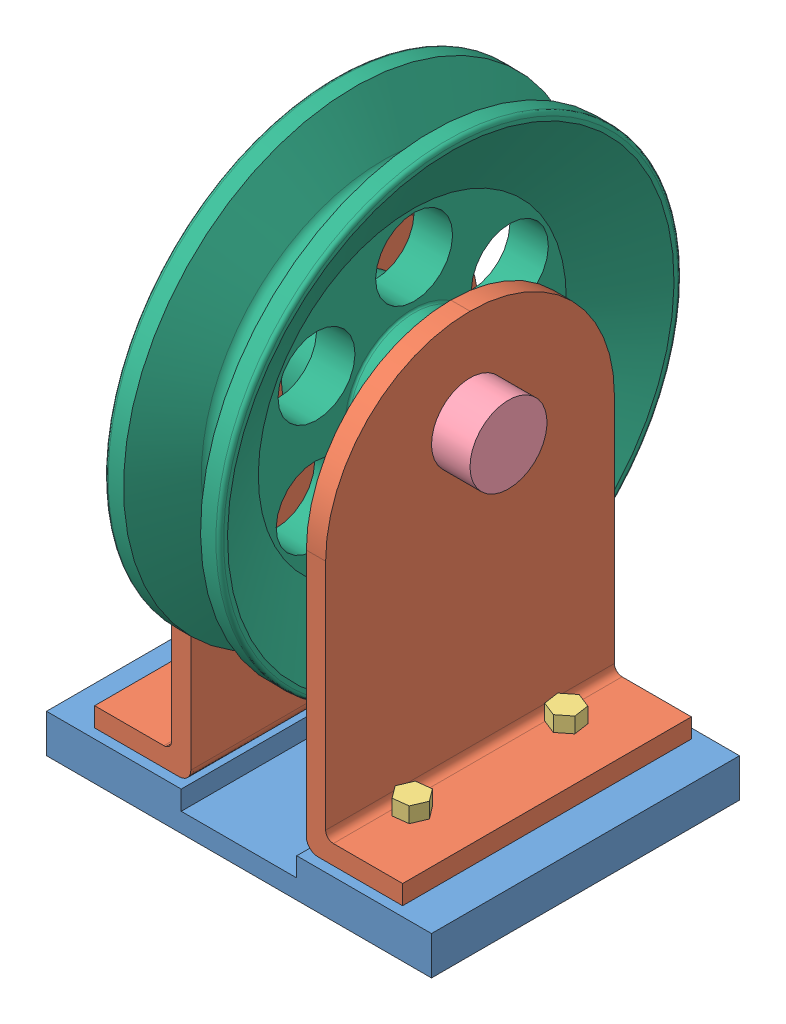
SolidWorks assembly pulley-assembly, configuration Default. Lengths in mm.
Overall size (2540 3846.4 3097.4).
10 component instances, 6 part files, 24 mates.
Components (placement in the parent):
- Base Plate-1: Base Plate [Default] at (1082.0609 1041.9855 1985.3264) size (2540 254 2032)
- Bracket-2: Bracket [Default] at (1463.0609 1295.9855 1032.8264) x (0 0 -1) z (1 0 0) size (1905 2724.15 698.5)
- Bracket-3: Bracket [Default] at (701.0609 1295.9855 2937.8264) x (0 0 1) z (-1 0 0) size (1905 2724.15 698.5)
- Bolt-1: Bolt [Default] at (1717.0609 1422.9855 2493.3264) x (0.390029 0 -0.920802) z (0.920802 0 0.390029) size (202.45 355.6 175.33)
- Bolt-2: Bolt [Default] at (1717.0609 1422.9855 1477.3264) x (0.783764 0 -0.621058) z (0.621058 0 0.783764) size (202.45 355.6 175.33)
- Bolt-3: Bolt [Default] at (447.0609 1422.9855 2493.3264) x (0.04355 0 0.999051) z (-0.999051 0 0.04355) size (202.45 355.6 175.33)
- Bolt-4: Bolt [Default] at (447.0609 1422.9855 1477.3264) x (0.143571 0 -0.98964) z (0.98964 0 0.143571) size (202.45 355.6 175.33)
- Axle-1: Axle [Default] at (574.0609 3327.9855 1985.3264) x (0 0.016342 0.999866) z (0 -0.999866 0.016342) size (670.56 1816.1 609.6)
- Key-1: Key [Default] at (1082.0609 3480.3651 1982.836) x (1 0 0) z (0 0.016342 0.999866) size (635 203.2 152.4)
- Pulley Week 8-1: Pulley Week 8 [Default] at (1082.0609 3339.6833 1985.1352) x (0 -0.016342 -0.999866) z (0 -0.999866 0.016342) size (3048 762 3048)
Mates (geometry in assembly coordinates):
- Coincident20: coincident anti-aligned: plane of Base Plate-1 through (1082.0609 1295.9855 1985.3264) normal (0 1 0); plane of Bracket-2 through (2098.0609 1295.9855 2937.8264) normal (0 -1 0)
- Coincident21: coincident aligned: circle of Base Plate-1; circle of Bracket-2
- Coincident22: coincident aligned: circle of Base Plate-1; circle of Bracket-2
- Coincident23: coincident anti-aligned: plane of Base Plate-1 through (1082.0609 1295.9855 1985.3264) normal (0 1 0); plane of Bracket-3 through (66.0609 1295.9855 1032.8264) normal (0 -1 0)
- Coincident24: coincident aligned: circle of Base Plate-1; circle of Bracket-3
- Coincident25: coincident aligned: circle of Base Plate-1; circle of Bracket-3
- Concentric1: concentric aligned: cylinder of Base Plate-1 through (447.0609 1295.9855 2493.3264) axis (0 1 0) radius 63.5; cylinder of Bolt-3 through (447.0609 1168.9855 2493.3264) axis (0 1 0) radius 63.5
- Coincident26: coincident anti-aligned: plane of Bracket-3 through (574.0609 1422.9855 1032.8264) normal (0 1 0); plane of Bolt-3 through (447.0609 1422.9855 2493.3264) normal (0 -1 0)
- Concentric2: concentric aligned: cylinder of Base Plate-1 through (1717.0609 1295.9855 2493.3264) axis (0 1 0) radius 63.5; cylinder of Bolt-1 through (1717.0609 1168.9855 2493.3264) axis (0 1 0) radius 63.5
- Concentric3: concentric aligned: cylinder of Base Plate-1 through (1717.0609 1295.9855 1477.3264) axis (0 1 0) radius 63.5; cylinder of Bolt-2 through (1717.0609 1168.9855 1477.3264) axis (0 1 0) radius 63.5
- Concentric4: concentric aligned: cylinder of Base Plate-1 through (447.0609 1295.9855 1477.3264) axis (0 1 0) radius 63.5; cylinder of Bolt-4 through (447.0609 1168.9855 1477.3264) axis (0 1 0) radius 63.5
- Coincident27: coincident anti-aligned: plane of Bracket-2 through (1590.0609 1422.9855 2937.8264) normal (0 1 0); plane of Bolt-1 through (1717.0609 1422.9855 2493.3264) normal (0 -1 0)
- Coincident28: coincident anti-aligned: plane of Bracket-2 through (1590.0609 1422.9855 2937.8264) normal (0 1 0); plane of Bolt-2 through (1717.0609 1422.9855 1477.3264) normal (0 -1 0)
- Coincident29: coincident anti-aligned: plane of Bracket-3 through (574.0609 1422.9855 1032.8264) normal (0 1 0); plane of Bolt-4 through (447.0609 1422.9855 1477.3264) normal (0 -1 0)
- Concentric5: concentric anti-aligned: cylinder of Bracket-2 through (1463.0609 3327.9855 1985.3264) axis (1 0 0) radius 254; cylinder of Axle-1 through (1844.0609 3327.9855 1985.3264) axis (-1 0 0) radius 254
- Coincident30: coincident anti-aligned: plane of Bracket-3 through (574.0609 3962.9855 1032.8264) normal (-1 0 0); plane of Axle-1 through (574.0609 3327.9855 1985.3264) normal (1 0 0)
- Coincident31: coincident anti-aligned: plane of Axle-1 through (574.0609 3480.3651 1982.836) normal (0 0.999866 -0.016342); plane of Key-1 through (1082.0609 3480.3651 1982.836) normal (0 -0.999866 0.016342)
- Coincident32: coincident anti-aligned: plane of Axle-1 through (1399.5609 3479.1199 1906.6461) normal (0 0.016342 0.999866); plane of Key-1 through (1399.5609 3682.2928 1903.3255) normal (0 -0.016342 -0.999866)
- Coincident34: coincident anti-aligned: plane of Axle-1 through (1399.5609 3479.1199 1906.6461) normal (-1 0 0); plane of Key-1 through (1399.5609 3684.7832 2055.7052) normal (1 0 0)
- Lock2: lock: unknown of Axle-1; unknown of Key-1
- Coincident35: coincident anti-aligned: plane of Key-1 through (1082.0609 3683.538 1979.5154) normal (0 0.999866 -0.016342); plane of Pulley Week 8-1 through (701.0609 3684.7832 2055.7052) normal (0 -0.999866 0.016342)
- Coincident36: coincident anti-aligned: plane of Key-1 through (1399.5609 3684.7832 2055.7052) normal (0 0.016342 0.999866); plane of Pulley Week 8-1 through (701.0609 3583.1968 2057.3655) normal (0 -0.016342 -0.999866)
- Coincident37: coincident aligned: plane of Base Plate-1 through (1082.0609 1041.9855 1985.3264) normal (1 0 0); plane of Pulley Week 8-1 through (1082.0609 3339.6833 1985.1352) normal (1 0 0)
- Lock3: lock: unknown of Key-1; unknown of Pulley Week 8-1
